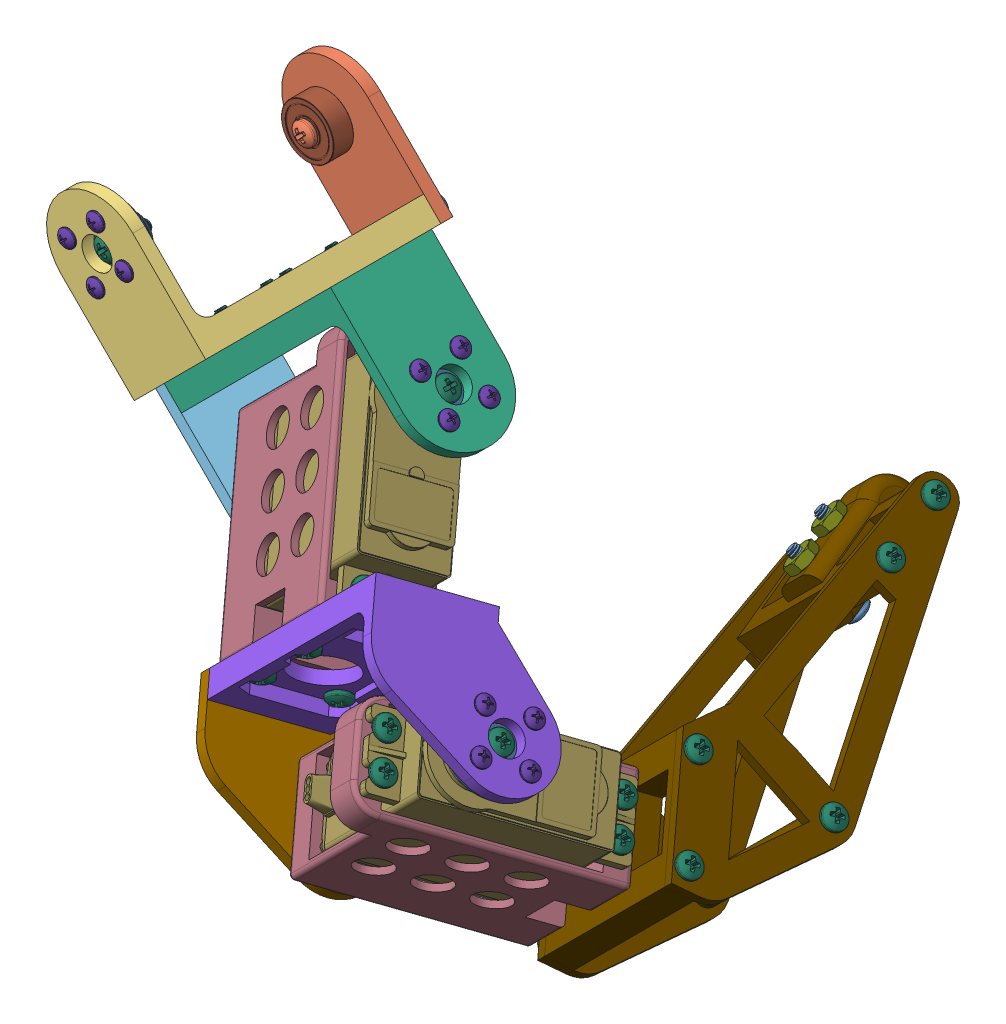
SolidWorks assembly 复件 Assembly - Leg_3, configuration 默认. Lengths in mm.
Overall size (162.92 162.92 153.05).
89 component instances, 20 part files, 0 mates.
Components (placement in the parent):
- Assembly1_3-1: Assembly1_3 [默认] at origin size (162.92 162.92 153.05)
  - Femur Bracket_6^Assembly1_3_复件 Assembly - Leg_3_Hexapod-1: Femur Bracket_6^Assembly1_3_复件 Assembly - Leg_3_Hexapod [默认] at (-252.2608 -61.089 -9.5835) x (-0.707107 -0.707107 0) z (0 0 -1) size (25 38 63.16) (virtual)
    - 4-40 x 0.500^Femur Bracket_6_Assembly1_3_复件 Assembly - Leg_3_Hexapod-1: 4-40 x 0.500^Femur Bracket_6_Assembly1_3_复件 Assembly - Leg_3_Hexapod [默认] at (-8.75 -18.6477 12.1944) size (5.56 5.56 14.67) (virtual)
    - 4-40 x 0.500^Femur Bracket_6_Assembly1_3_复件 Assembly - Leg_3_Hexapod-2: 4-40 x 0.500^Femur Bracket_6_Assembly1_3_复件 Assembly - Leg_3_Hexapod [默认] at (8.75 -18.6477 12.1944) size (5.56 5.56 14.67) (virtual)
    - Femur Bracket_6-27^Femur Bracket_6_Assembly1_3_复件 Assembly - Leg_3_Hexapod-1: Femur Bracket_6-27^Femur Bracket_6_Assembly1_3_复件 Assembly - Leg_3_Hexapod [默认] at origin size (25 38 3) (virtual)
    - Femur Bracket_6-28^Femur Bracket_6_Assembly1_3_复件 Assembly - Leg_3_Hexapod-1: Femur Bracket_6-28^Femur Bracket_6_Assembly1_3_复件 Assembly - Leg_3_Hexapod [默认] at origin size (25 38 58.2) (virtual)
  - Femur Bracket_7^Assembly1_3_复件 Assembly - Leg_3_Hexapod-1: Femur Bracket_7^Assembly1_3_复件 Assembly - Leg_3_Hexapod [默认] at (-225.6808 -95.738 -3.8779) x (0 0 -1) z (-0.707107 -0.707107 0) size (25 38 63.16) (virtual)
    - 4-40 x 0.500^Femur Bracket_7_Assembly1_3_复件 Assembly - Leg_3_Hexapod-1: 4-40 x 0.500^Femur Bracket_7_Assembly1_3_复件 Assembly - Leg_3_Hexapod [默认] at (-8.75 -18.6477 12.1944) size (5.56 5.56 14.67) (virtual)
    - 4-40 x 0.500^Femur Bracket_7_Assembly1_3_复件 Assembly - Leg_3_Hexapod-2: 4-40 x 0.500^Femur Bracket_7_Assembly1_3_复件 Assembly - Leg_3_Hexapod [默认] at (8.75 -18.6477 12.1944) size (5.56 5.56 14.67) (virtual)
    - Femur Bracket_7-29^Femur Bracket_7_Assembly1_3_复件 Assembly - Leg_3_Hexapod-1: Femur Bracket_7-29^Femur Bracket_7_Assembly1_3_复件 Assembly - Leg_3_Hexapod [默认] at origin size (25 38 3) (virtual)
    - Femur Bracket_7-30^Femur Bracket_7_Assembly1_3_复件 Assembly - Leg_3_Hexapod-1: Femur Bracket_7-30^Femur Bracket_7_Assembly1_3_复件 Assembly - Leg_3_Hexapod [默认] at origin size (25 38 58.2) (virtual)
  - Tibia Bracket_3^Assembly1_3_复件 Assembly - Leg_3_Hexapod-1: Tibia Bracket_3^Assembly1_3_复件 Assembly - Leg_3_Hexapod [默认] at (-186.1371 -124.036 33.1424) x (0.454519 -0.454519 -0.766044) z (0.707107 0.707107 0) size (39.5 35 63.16) (virtual)
    - 4-40 x 0.375^Tibia Bracket_3_Assembly1_3_复件 Assembly - Leg_3_Hexapod-1: 4-40 x 0.375^Tibia Bracket_3_Assembly1_3_复件 Assembly - Leg_3_Hexapod [默认] at (8.75 15.8933 -23.4324) x (1 0 0) z (0 0 -1) size (5.56 5.56 11.49) (virtual)
    - 4-40 x 0.375^Tibia Bracket_3_Assembly1_3_复件 Assembly - Leg_3_Hexapod-2: 4-40 x 0.375^Tibia Bracket_3_Assembly1_3_复件 Assembly - Leg_3_Hexapod [默认] at (-8.75 15.8933 -23.4324) x (1 0 0) z (0 0 -1) size (5.56 5.56 11.49) (virtual)
    - Tibia Bracket_3-31^Tibia Bracket_3_Assembly1_3_复件 Assembly - Leg_3_Hexapod-1: Tibia Bracket_3-31^Tibia Bracket_3_Assembly1_3_复件 Assembly - Leg_3_Hexapod [默认] at origin size (39.5 35 58.2) (virtual)
    - Tibia Bracket_3-32^Tibia Bracket_3_Assembly1_3_复件 Assembly - Leg_3_Hexapod-1: Tibia Bracket_3-32^Tibia Bracket_3_Assembly1_3_复件 Assembly - Leg_3_Hexapod [默认] at origin size (39.5 35 3) (virtual)
  - Servo Wheel^Assembly1_3_复件 Assembly - Leg_3_Hexapod-1: Servo Wheel^Assembly1_3_复件 Assembly - Leg_3_Hexapod [默认] at (-259.2302 -49.3113 -32.7562) x (0.707107 0.707107 0) z (0.707107 -0.707107 0) size (20 6.72 20) (virtual)
  - 624Z Bearing^Assembly1_3_复件 Assembly - Leg_3_Hexapod-1: 624Z Bearing^Assembly1_3_复件 Assembly - Leg_3_Hexapod [默认] at (-268.9855 -57.7993 -22.889) x (0.707107 0.707107 0) z (0.707107 -0.707107 0) size (13 5 13) (virtual)
  - Servo Wheel^Assembly1_3_复件 Assembly - Leg_3_Hexapod-2: Servo Wheel^Assembly1_3_复件 Assembly - Leg_3_Hexapod [默认] at (-232.6928 -121.4971 -0.4779) x (0 0 1) z (-0.707107 0.707107 0) size (20 6.72 20) (virtual)
  - Servo MG996R^Assembly1_3_复件 Assembly - Leg_3_Hexapod-2: Servo MG996R^Assembly1_3_复件 Assembly - Leg_3_Hexapod [默认] at (-226.2038 -112.7591 2.6786) x (-0.454519 0.454519 0.766044) z (-0.541675 0.541675 -0.642788) size (19 43.25 54) (virtual)
  - Servo Mount^Assembly1_3_复件 Assembly - Leg_3_Hexapod-2: Servo Mount^Assembly1_3_复件 Assembly - Leg_3_Hexapod [默认] at (-222.6505 -117.3269 -4.9043) x (-0.454519 0.454519 0.766044) z (-0.541675 0.541675 -0.642788) size (23.3 35.7 57) (virtual)
  - 624Z Bearing^Assembly1_3_复件 Assembly - Leg_3_Hexapod-2: 624Z Bearing^Assembly1_3_复件 Assembly - Leg_3_Hexapod [默认] at (-240.5893 -113.7885 -17.6474) x (-0.454519 0.454519 0.766044) z (0.541675 -0.541675 0.642788) size (13 5 13) (virtual)
  - Bearing Center^Assembly1_3_复件 Assembly - Leg_3_Hexapod-1: Bearing Center^Assembly1_3_复件 Assembly - Leg_3_Hexapod [默认] at (-255.0555 -58.2943 -31.389) x (0.707107 0.707107 0) z (0.707107 -0.707107 0) size (9 6 9) (virtual)
  - Bearing Center^Assembly1_3_复件 Assembly - Leg_3_Hexapod-2: Bearing Center^Assembly1_3_复件 Assembly - Leg_3_Hexapod [默认] at (-238.3215 -113.935 -3.8136) x (-0.454519 0.454519 0.766044) z (-0.541675 0.541675 -0.642788) size (9 6 9) (virtual)
  - 4-40 x 0.375^Assembly1_3_复件 Assembly - Leg_3_Hexapod-1: 4-40 x 0.375^Assembly1_3_复件 Assembly - Leg_3_Hexapod [默认] at (-235.9106 -66.1255 4.1221) x (0 0 1) z (0.707107 -0.707107 0) size (5.56 5.56 11.49) (virtual)
  - 4-40 x 0.375^Assembly1_3_复件 Assembly - Leg_3_Hexapod-2: 4-40 x 0.375^Assembly1_3_复件 Assembly - Leg_3_Hexapod [默认] at (-247.2243 -77.4392 -11.8779) x (0 0 1) z (0.707107 -0.707107 0) size (5.56 5.56 11.49) (virtual)
  - 4-40 x 0.375^Assembly1_3_复件 Assembly - Leg_3_Hexapod-3: 4-40 x 0.375^Assembly1_3_复件 Assembly - Leg_3_Hexapod [默认] at (-247.2243 -77.4392 4.1221) x (0 0 1) z (0.707107 -0.707107 0) size (5.56 5.56 11.49) (virtual)
  - 4-40 x 0.375^Assembly1_3_复件 Assembly - Leg_3_Hexapod-4: 4-40 x 0.375^Assembly1_3_复件 Assembly - Leg_3_Hexapod [默认] at (-235.9106 -66.1255 -11.8779) x (0 0 1) z (0.707107 -0.707107 0) size (5.56 5.56 11.49) (virtual)
  - 4-40 Nut^Assembly1_3_复件 Assembly - Leg_3_Hexapod-1: 4-40 Nut^Assembly1_3_复件 Assembly - Leg_3_Hexapod [默认] at (-245.5736 -79.0899 -11.8779) x (-0.353553 -0.353553 0.866025) z (0.612372 0.612372 0.5) size (6.35 2.39 7.33) (virtual)
  - 4-40 Nut^Assembly1_3_复件 Assembly - Leg_3_Hexapod-2: 4-40 Nut^Assembly1_3_复件 Assembly - Leg_3_Hexapod [默认] at (-234.2599 -67.7762 -11.8779) x (-0.353553 -0.353553 0.866025) z (0.612372 0.612372 0.5) size (6.35 2.39 7.33) (virtual)
  - 4-40 Nut^Assembly1_3_复件 Assembly - Leg_3_Hexapod-3: 4-40 Nut^Assembly1_3_复件 Assembly - Leg_3_Hexapod [默认] at (-234.2599 -67.7762 4.1221) x (-0.353553 -0.353553 0.866025) z (0.612372 0.612372 0.5) size (6.35 2.39 7.33) (virtual)
  - 4-40 Nut^Assembly1_3_复件 Assembly - Leg_3_Hexapod-4: 4-40 Nut^Assembly1_3_复件 Assembly - Leg_3_Hexapod [默认] at (-245.5736 -79.0899 4.1221) x (-0.353553 -0.353553 0.866025) z (0.612372 0.612372 0.5) size (6.35 2.39 7.33) (virtual)
  - Blunt #2 0.25^Assembly1_3_复件 Assembly - Leg_3_Hexapod-1: Blunt #2 0.25^Assembly1_3_复件 Assembly - Leg_3_Hexapod [默认] at (-195.9944 -78.5706 1.1221) x (0.707107 -0.707107 0) z (0.707107 0.707107 0) size (4.24 4.24 7.89) (virtual)
  - Blunt #2 0.25^Assembly1_3_复件 Assembly - Leg_3_Hexapod-2: Blunt #2 0.25^Assembly1_3_复件 Assembly - Leg_3_Hexapod [默认] at (-254.9848 -65.4361 23.5471) x (-0.707107 0.707107 0) z (0 0 1) size (4.24 4.24 7.89) (virtual)
  - Blunt #2 0.25^Assembly1_3_复件 Assembly - Leg_3_Hexapod-3: Blunt #2 0.25^Assembly1_3_复件 Assembly - Leg_3_Hexapod [默认] at (-247.9137 -58.365 23.5471) x (-0.707107 0.707107 0) z (0 0 1) size (4.24 4.24 7.89) (virtual)
  - Blunt #2 0.25^Assembly1_3_复件 Assembly - Leg_3_Hexapod-4: Blunt #2 0.25^Assembly1_3_复件 Assembly - Leg_3_Hexapod [默认] at (-254.9848 -51.294 23.5471) x (0.707107 -0.707107 0) z (0 0 1) size (4.24 4.24 7.89) (virtual)
  - Blunt #2 0.25^Assembly1_3_复件 Assembly - Leg_3_Hexapod-5: Blunt #2 0.25^Assembly1_3_复件 Assembly - Leg_3_Hexapod [默认] at (-203.0655 -71.4995 -8.8779) x (0.707107 -0.707107 0) z (0.707107 0.707107 0) size (4.24 4.24 7.89) (virtual)
  - Blunt #2 0.25^Assembly1_3_复件 Assembly - Leg_3_Hexapod-6: Blunt #2 0.25^Assembly1_3_复件 Assembly - Leg_3_Hexapod [默认] at (-203.0655 -71.4995 1.1221) x (0.707107 -0.707107 0) z (0.707107 0.707107 0) size (4.24 4.24 7.89) (virtual)
  - Blunt #2 0.25^Assembly1_3_复件 Assembly - Leg_3_Hexapod-7: Blunt #2 0.25^Assembly1_3_复件 Assembly - Leg_3_Hexapod [默认] at (-195.9944 -78.5706 -8.8779) x (0.707107 -0.707107 0) z (0.707107 0.707107 0) size (4.24 4.24 7.89) (virtual)
  - Blunt #2 0.25^Assembly1_3_复件 Assembly - Leg_3_Hexapod-8: Blunt #2 0.25^Assembly1_3_复件 Assembly - Leg_3_Hexapod [默认] at (-262.0559 -58.365 23.5471) x (-0.707107 0.707107 0) z (0 0 1) size (4.24 4.24 7.89) (virtual)
  - Servo Mount^Assembly1_3_复件 Assembly - Leg_3_Hexapod-3: Servo Mount^Assembly1_3_复件 Assembly - Leg_3_Hexapod [默认] at (-191.8085 -148.3328 10.6121) x (0.541675 -0.541675 0.642788) z (-0.454519 0.454519 0.766044) size (23.3 35.7 57) (virtual)
  - Servo MG996R^Assembly1_3_复件 Assembly - Leg_3_Hexapod-3: Servo MG996R^Assembly1_3_复件 Assembly - Leg_3_Hexapod [默认] at (-185.9394 -153.1874 16.3546) x (0.541675 -0.541675 0.642788) z (-0.454519 0.454519 0.766044) size (19 43.25 54) (virtual)
  - Servo Wheel^Assembly1_3_复件 Assembly - Leg_3_Hexapod-3: Servo Wheel^Assembly1_3_复件 Assembly - Leg_3_Hexapod [默认] at (-194.6372 -159.71 32.8175) x (-0.454519 0.454519 0.766044) z (-0.541675 0.541675 -0.642788) size (20 6.72 20) (virtual)
  - 624Z Bearing^Assembly1_3_复件 Assembly - Leg_3_Hexapod-3: 624Z Bearing^Assembly1_3_复件 Assembly - Leg_3_Hexapod [默认] at (-208.0195 -146.5222 25.7988) x (0.541675 -0.541675 0.642788) z (0.454519 -0.454519 -0.766044) size (13 5 13) (virtual)
  - Bearing Center^Assembly1_3_复件 Assembly - Leg_3_Hexapod-3: Bearing Center^Assembly1_3_复件 Assembly - Leg_3_Hexapod [默认] at (-197.1768 -155.2435 24.0916) x (0.541675 -0.541675 0.642788) z (-0.454519 0.454519 0.766044) size (9 6 9) (virtual)
  - Blunt #2 0.25^Assembly1_3_复件 Assembly - Leg_3_Hexapod-9: Blunt #2 0.25^Assembly1_3_复件 Assembly - Leg_3_Hexapod [默认] at (-158.809 -115.9132 17.1241) x (-0.541675 0.541675 -0.642788) z (0.707107 0.707107 0) size (4.24 4.24 7.89) (virtual)
  - Blunt #2 0.25^Assembly1_3_复件 Assembly - Leg_3_Hexapod-10: Blunt #2 0.25^Assembly1_3_复件 Assembly - Leg_3_Hexapod [默认] at (-163.3542 -111.3681 24.7845) x (-0.541675 0.541675 -0.642788) z (0.707107 0.707107 0) size (4.24 4.24 7.89) (virtual)
  - Blunt #2 0.25^Assembly1_3_复件 Assembly - Leg_3_Hexapod-11: Blunt #2 0.25^Assembly1_3_复件 Assembly - Leg_3_Hexapod [默认] at (-157.9374 -116.7848 31.2124) x (-0.541675 0.541675 -0.642788) z (0.707107 0.707107 0) size (4.24 4.24 7.89) (virtual)
  - Blunt #2 0.25^Assembly1_3_复件 Assembly - Leg_3_Hexapod-12: Blunt #2 0.25^Assembly1_3_复件 Assembly - Leg_3_Hexapod [默认] at (-153.3922 -121.33 23.5519) x (-0.541675 0.541675 -0.642788) z (0.707107 0.707107 0) size (4.24 4.24 7.89) (virtual)
  - Tibia Assembly^Assembly1_3_复件 Assembly - Leg_3_Hexapod-1: Tibia Assembly^Assembly1_3_复件 Assembly - Leg_3_Hexapod [默认] at (-177.9003 -135.4496 -94.4853) x (0.707107 0.707107 0) z (0.541675 -0.541675 0.642788) size (46.8 55.22 97.3) (virtual)
  - 4-40 x 0.625^Assembly1_3_复件 Assembly - Leg_3_Hexapod-1: 4-40 x 0.625^Assembly1_3_复件 Assembly - Leg_3_Hexapod [默认] at (-180.626 -132.7239 -70.5014) x (0.244517 -0.244517 0.938308) z (0.663484 -0.663484 -0.3458) size (5.56 5.56 17.84) (virtual)
  - 4-40 x 0.625^Assembly1_3_复件 Assembly - Leg_3_Hexapod-2: 4-40 x 0.625^Assembly1_3_复件 Assembly - Leg_3_Hexapod [默认] at (-183.0711 -130.2787 -79.8845) x (0.244517 -0.244517 0.938308) z (0.663484 -0.663484 -0.3458) size (5.56 5.56 17.84) (virtual)
  - 4-40 Nut^Assembly1_3_复件 Assembly - Leg_3_Hexapod-5: 4-40 Nut^Assembly1_3_复件 Assembly - Leg_3_Hexapod [默认] at (-178.8461 -134.5038 -71.4225) x (0.245085 -0.245085 0.938012) z (0.707107 0.707107 0) size (6.35 2.39 7.33) (virtual)
  - 4-40 Nut^Assembly1_3_复件 Assembly - Leg_3_Hexapod-6: 4-40 Nut^Assembly1_3_复件 Assembly - Leg_3_Hexapod [默认] at (-181.2969 -132.053 -80.8026) x (0.245085 -0.245085 0.938012) z (0.707107 0.707107 0) size (6.35 2.39 7.33) (virtual)
  - 4-40 x 0.375^Assembly1_3_复件 Assembly - Leg_3_Hexapod-5: 4-40 x 0.375^Assembly1_3_复件 Assembly - Leg_3_Hexapod [默认] at (-227.1527 -83.8441 -9.4926) x (-0.454519 0.454519 0.766044) z (0.707107 0.707107 0) size (5.56 5.56 11.49) (virtual)
  - 4-40 x 0.375^Assembly1_3_复件 Assembly - Leg_3_Hexapod-6: 4-40 x 0.375^Assembly1_3_复件 Assembly - Leg_3_Hexapod [默认] at (-223.2892 -87.7076 -16.004) x (-0.454519 0.454519 0.766044) z (0.707107 0.707107 0) size (5.56 5.56 11.49) (virtual)
  - 4-40 x 0.375^Assembly1_3_复件 Assembly - Leg_3_Hexapod-11: 4-40 x 0.375^Assembly1_3_复件 Assembly - Leg_3_Hexapod [默认] at (-201.1523 -109.8446 21.3612) x (-0.454519 0.454519 0.766044) z (0.707107 0.707107 0) size (5.56 5.56 11.49) (virtual)
  - 4-40 x 0.375^Assembly1_3_复件 Assembly - Leg_3_Hexapod-12: 4-40 x 0.375^Assembly1_3_复件 Assembly - Leg_3_Hexapod [默认] at (-197.2888 -113.708 14.8498) x (-0.454519 0.454519 0.766044) z (0.707107 0.707107 0) size (5.56 5.56 11.49) (virtual)
  - 4-40 x 0.375^Assembly1_3_复件 Assembly - Leg_3_Hexapod-13: 4-40 x 0.375^Assembly1_3_复件 Assembly - Leg_3_Hexapod [默认] at (-180.5627 -130.598 37.4715) x (0.541675 -0.541675 0.642788) z (0.707107 0.707107 0) size (5.56 5.56 11.49) (virtual)
  - 4-40 x 0.375^Assembly1_3_复件 Assembly - Leg_3_Hexapod-14: 4-40 x 0.375^Assembly1_3_复件 Assembly - Leg_3_Hexapod [默认] at (-185.1669 -125.9938 32.0078) x (0.541675 -0.541675 0.642788) z (0.707107 0.707107 0) size (5.56 5.56 11.49) (virtual)
  - 4-40 x 0.375^Assembly1_3_复件 Assembly - Leg_3_Hexapod-15: 4-40 x 0.375^Assembly1_3_复件 Assembly - Leg_3_Hexapod [默认] at (-158.7457 -152.4149 0.7013) x (0.541675 -0.541675 0.642788) z (0.707107 0.707107 0) size (5.56 5.56 11.49) (virtual)
  - 4-40 x 0.375^Assembly1_3_复件 Assembly - Leg_3_Hexapod-16: 4-40 x 0.375^Assembly1_3_复件 Assembly - Leg_3_Hexapod [默认] at (-163.35 -147.8107 -4.7623) x (0.541675 -0.541675 0.642788) z (0.707107 0.707107 0) size (5.56 5.56 11.49) (virtual)
  - 4-40 x 0.500^Assembly1_3_复件 Assembly - Leg_3_Hexapod-1: 4-40 x 0.500^Assembly1_3_复件 Assembly - Leg_3_Hexapod [默认] at (-159.6766 -155.4085 4.7971) x (0.541675 -0.541675 0.642788) z (0.454519 -0.454519 -0.766044) size (5.56 5.56 14.67) (virtual)
  - 4-40 x 0.500^Assembly1_3_复件 Assembly - Leg_3_Hexapod-2: 4-40 x 0.500^Assembly1_3_复件 Assembly - Leg_3_Hexapod [默认] at (-168.3434 -146.7417 -5.4875) x (0.541675 -0.541675 0.642788) z (0.454519 -0.454519 -0.766044) size (5.56 5.56 14.67) (virtual)
  - 4-40 x 0.500^Assembly1_3_复件 Assembly - Leg_3_Hexapod-3: 4-40 x 0.500^Assembly1_3_复件 Assembly - Leg_3_Hexapod [默认] at (-170.9903 -166.7222 4.7971) x (0.541675 -0.541675 0.642788) z (0.454519 -0.454519 -0.766044) size (5.56 5.56 14.67) (virtual)
  - 4-40 x 0.500^Assembly1_3_复件 Assembly - Leg_3_Hexapod-4: 4-40 x 0.500^Assembly1_3_复件 Assembly - Leg_3_Hexapod [默认] at (-179.6571 -158.0554 -5.4875) x (0.541675 -0.541675 0.642788) z (0.454519 -0.454519 -0.766044) size (5.56 5.56 14.67) (virtual)
  - 4-40 x 0.375^Assembly1_3_复件 Assembly - Leg_3_Hexapod-17: 4-40 x 0.375^Assembly1_3_复件 Assembly - Leg_3_Hexapod [默认] at (-183.1515 -149.8206 -71.0986) x (0.541675 -0.541675 0.642788) z (-0.707107 -0.707107 0) size (5.56 5.56 11.49) (virtual)
  - 4-40 x 0.375^Assembly1_3_复件 Assembly - Leg_3_Hexapod-18: 4-40 x 0.375^Assembly1_3_复件 Assembly - Leg_3_Hexapod [默认] at (-163.5292 -130.1984 -71.0986) x (-0.454519 0.454519 0.766044) z (0.707107 0.707107 0) size (5.56 5.56 11.49) (virtual)
  - 4-40 x 0.375^Assembly1_3_复件 Assembly - Leg_3_Hexapod-19: 4-40 x 0.375^Assembly1_3_复件 Assembly - Leg_3_Hexapod [默认] at (-187.0683 -145.9038 -86.1092) x (0.541675 -0.541675 0.642788) z (-0.707107 -0.707107 0) size (5.56 5.56 11.49) (virtual)
  - 4-40 x 0.375^Assembly1_3_复件 Assembly - Leg_3_Hexapod-20: 4-40 x 0.375^Assembly1_3_复件 Assembly - Leg_3_Hexapod [默认] at (-167.4461 -126.2816 -86.1092) x (-0.454519 0.454519 0.766044) z (0.707107 0.707107 0) size (5.56 5.56 11.49) (virtual)
  - 4-40 x 0.375^Assembly1_3_复件 Assembly - Leg_3_Hexapod-21: 4-40 x 0.375^Assembly1_3_复件 Assembly - Leg_3_Hexapod [默认] at (-162.5862 -170.3858 -0.7052) x (0.541675 -0.541675 0.642788) z (-0.707107 -0.707107 0) size (5.56 5.56 11.49) (virtual)
  - 4-40 x 0.375^Assembly1_3_复件 Assembly - Leg_3_Hexapod-22: 4-40 x 0.375^Assembly1_3_复件 Assembly - Leg_3_Hexapod [默认] at (-154.8809 -138.8468 -14.8465) x (-0.454519 0.454519 0.766044) z (0.707107 0.707107 0) size (5.56 5.56 11.49) (virtual)
  - 4-40 x 0.375^Assembly1_3_复件 Assembly - Leg_3_Hexapod-23: 4-40 x 0.375^Assembly1_3_复件 Assembly - Leg_3_Hexapod [默认] at (-142.964 -150.7636 -0.7052) x (-0.454519 0.454519 0.766044) z (0.707107 0.707107 0) size (5.56 5.56 11.49) (virtual)
  - 4-40 x 0.375^Assembly1_3_复件 Assembly - Leg_3_Hexapod-24: 4-40 x 0.375^Assembly1_3_复件 Assembly - Leg_3_Hexapod [默认] at (-158.7973 -174.1748 -32.7604) x (0.541675 -0.541675 0.642788) z (-0.707107 -0.707107 0) size (5.56 5.56 11.49) (virtual)
  - 4-40 x 0.375^Assembly1_3_复件 Assembly - Leg_3_Hexapod-25: 4-40 x 0.375^Assembly1_3_复件 Assembly - Leg_3_Hexapod [默认] at (-174.5031 -158.469 -14.8465) x (0.541675 -0.541675 0.642788) z (-0.707107 -0.707107 0) size (5.56 5.56 11.49) (virtual)
  - 4-40 x 0.375^Assembly1_3_复件 Assembly - Leg_3_Hexapod-26: 4-40 x 0.375^Assembly1_3_复件 Assembly - Leg_3_Hexapod [默认] at (-139.1751 -154.5525 -32.7604) x (-0.454519 0.454519 0.766044) z (0.707107 0.707107 0) size (5.56 5.56 11.49) (virtual)
  - 4-40 x 0.375^Assembly1_3_复件 Assembly - Leg_3_Hexapod-27: 4-40 x 0.375^Assembly1_3_复件 Assembly - Leg_3_Hexapod [默认] at (-205.9158 -109.0054 22.9322) x (-0.454519 0.454519 0.766044) z (0.541675 -0.541675 0.642788) size (5.56 5.56 11.49) (virtual)
  - 4-40 x 0.375^Assembly1_3_复件 Assembly - Leg_3_Hexapod-28: 4-40 x 0.375^Assembly1_3_复件 Assembly - Leg_3_Hexapod [默认] at (-198.6435 -116.2777 10.6755) x (-0.454519 0.454519 0.766044) z (0.541675 -0.541675 0.642788) size (5.56 5.56 11.49) (virtual)
  - 4-40 x 0.375^Assembly1_3_复件 Assembly - Leg_3_Hexapod-29: 4-40 x 0.375^Assembly1_3_复件 Assembly - Leg_3_Hexapod [默认] at (-209.9572 -127.5915 10.6755) x (-0.454519 0.454519 0.766044) z (0.541675 -0.541675 0.642788) size (5.56 5.56 11.49) (virtual)
  - 4-40 x 0.375^Assembly1_3_复件 Assembly - Leg_3_Hexapod-30: 4-40 x 0.375^Assembly1_3_复件 Assembly - Leg_3_Hexapod [默认] at (-217.2295 -120.3191 22.9322) x (-0.454519 0.454519 0.766044) z (0.541675 -0.541675 0.642788) size (5.56 5.56 11.49) (virtual)
  - 4-40 x 0.375^Assembly1_3_复件 Assembly - Leg_3_Hexapod-31: 4-40 x 0.375^Assembly1_3_复件 Assembly - Leg_3_Hexapod [默认] at (-164.9846 -122.9605 24.1682) x (0.541675 -0.541675 0.642788) z (0.707107 0.707107 0) size (5.56 5.56 11.49) (virtual)
  - 4-40 x 0.375^Assembly1_3_复件 Assembly - Leg_3_Hexapod-32: 4-40 x 0.375^Assembly1_3_复件 Assembly - Leg_3_Hexapod [默认] at (-254.9848 -58.365 14.1971) x (0.707107 -0.707107 0) z (0 0 1) size (5.56 5.56 11.49) (virtual)
  - 4-40 x 0.375^Assembly1_3_复件 Assembly - Leg_3_Hexapod-33: 4-40 x 0.375^Assembly1_3_复件 Assembly - Leg_3_Hexapod [默认] at (-206.1414 -81.6465 -3.8779) x (0 0 1) z (0.707107 0.707107 0) size (5.56 5.56 11.49) (virtual)
  - 4-40 x 0.500^Assembly1_3_复件 Assembly - Leg_3_Hexapod-5: 4-40 x 0.500^Assembly1_3_复件 Assembly - Leg_3_Hexapod [默认] at (-201.9144 -159.9812 24.0916) x (0.541675 -0.541675 0.642788) z (0.707107 0.707107 0) size (5.56 5.56 14.67) (virtual)
  - 4-40 x 0.500^Assembly1_3_复件 Assembly - Leg_3_Hexapod-6: 4-40 x 0.500^Assembly1_3_复件 Assembly - Leg_3_Hexapod [默认] at (-255.0555 -58.2943 -38.089) x (0.707107 -0.707107 0) z (0 0 1) size (5.56 5.56 14.67) (virtual)
  - 4-40 x 0.500^Assembly1_3_复件 Assembly - Leg_3_Hexapod-7: 4-40 x 0.500^Assembly1_3_复件 Assembly - Leg_3_Hexapod [默认] at (-243.0591 -118.6726 -3.8136) x (0.541675 -0.541675 0.642788) z (0.707107 0.707107 0) size (5.56 5.56 14.67) (virtual)
  - 4-40 Nut^Assembly1_3_复件 Assembly - Leg_3_Hexapod-7: 4-40 Nut^Assembly1_3_复件 Assembly - Leg_3_Hexapod [默认] at (-254.9848 -58.365 -35.6685) x (0.707107 -0.707107 0) z (0.707107 0.707107 0) size (6.35 2.39 7.33) (virtual)
  - 4-40 Nut^Assembly1_3_复件 Assembly - Leg_3_Hexapod-8: 4-40 Nut^Assembly1_3_复件 Assembly - Leg_3_Hexapod [默认] at (-241.4017 -116.9068 -3.8779) x (0 0 1) z (0.707107 -0.707107 0) size (6.35 2.39 7.33) (virtual)
  - 4-40 Nut^Assembly1_3_复件 Assembly - Leg_3_Hexapod-9: 4-40 Nut^Assembly1_3_复件 Assembly - Leg_3_Hexapod [默认] at (-200.245 -158.2208 24.1682) x (0.541675 -0.541675 0.642788) z (-0.454519 0.454519 0.766044) size (6.35 2.39 7.33) (virtual)
